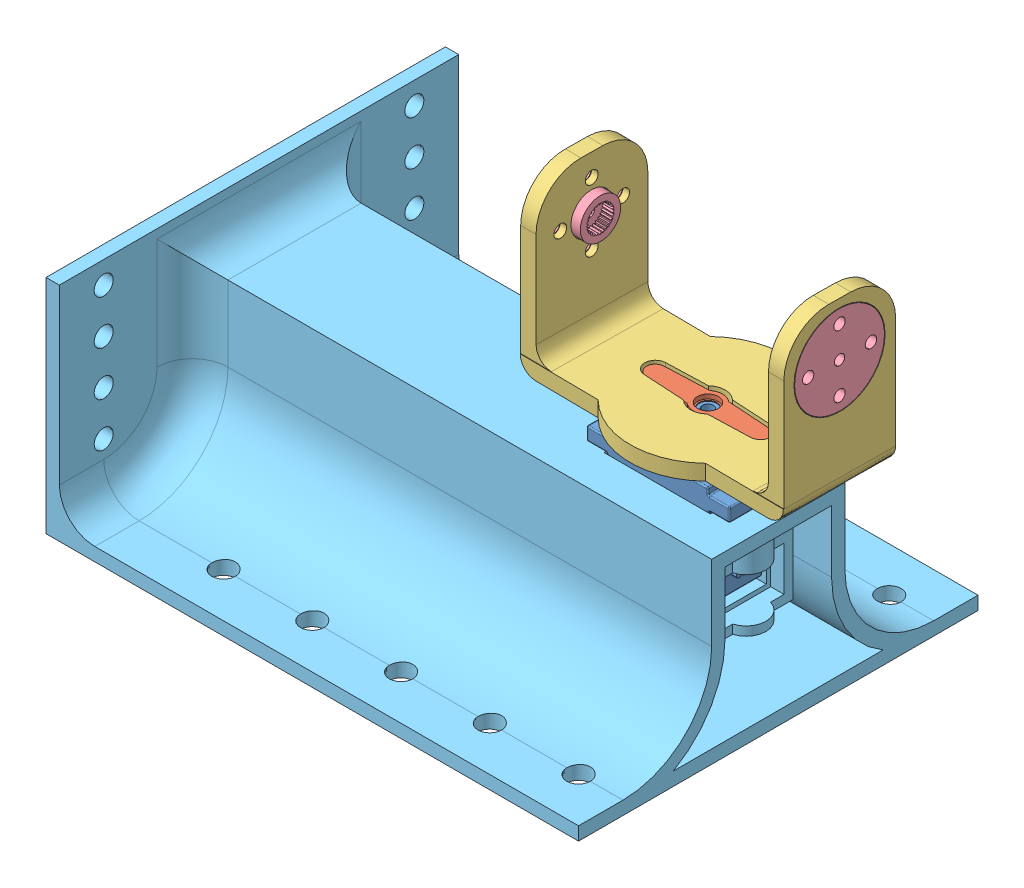
SolidWorks assembly CameraHolder, configuration Predeterminado. Lengths in mm.
Overall size (134.35 90.68 90).
6 component instances, 5 part files, 14 mates.
Components (placement in the parent):
- MG90S-1: MG90S [Default] at (-1.0795 -35.2179 32.5) size (32.2 32.5 12.4)
- Microservo horn-1: Microservo horn [По умолчанию] at (4.1705 -1.5379 32.5) x (0.999933 0 0.011606) z (0 -1 0) size (28 6.6 4.68)
- cameraHolder-1: cameraHolder [Predeterminado] at (4.1705 -4.5379 32.5) x (-0.011606 0 0.999933) z (-0.999933 0 -0.011606) size (35 40.2 60)
- MG955 horn-1: MG955 horn [Default] at (-23.8276 21.9621 32.175) x (0.011606 0 -0.999933) z (0 1 0) size (20 5.5 20)
- MG955 horn-4: MG955 horn [Default] at (32.1686 21.9621 32.825) x (-0.011606 0 0.999933) z (0 1 0) size (20 5.5 20)
- Soporte_motor-1: Soporte_motor [Predeterminado] at (20.0205 -36.7179 32.5) x (0 0 -1) z (1 0 0) size (90 50 120)
Mates (geometry in assembly coordinates):
- Concéntrica1: concentric aligned: cylinder of MG90S-1 through (4.1705 -5.2179 32.5) axis (0 1 0) radius 1.25; cylinder of Microservo horn-1 through (4.1705 -3.5379 32.5) axis (0 1 0) radius 2
- Coincidente1: coincident anti-aligned: plane of MG90S-1 through (4.1705 -6.2179 32.5) normal (0 1 0); plane of Microservo horn-1 through (4.1705 -6.2179 32.5) normal (0 -1 0)
- Concéntrica2: concentric aligned: cylinder of MG90S-1 through (4.1705 -5.2179 32.5) axis (0 1 0) radius 1.25; cylinder of cameraHolder-1 through (4.1705 -4.5379 32.5) axis (0 1 0) radius 3.6
- Distancia1: distance = 1 mm aligned: plane of Microservo horn-1 through (4.1705 -3.5379 32.5) normal (0 -1 0); plane of cameraHolder-1 through (4.1705 -4.5379 32.5) normal (0 -1 0)
- Coincidente3: coincident aligned: plane of Microservo horn-1 through (4.1705 -1.5379 32.5) normal (-0.011606 0 0.999933); plane of cameraHolder-1 through (4.1705 -4.5379 32.5) normal (-0.011606 0 0.999933)
- Coincidente4: coincident aligned: plane of cameraHolder-1 through (-25.8275 -4.5379 32.1518) normal (-0.999933 0 -0.011606); plane of MG955 horn-1 through (-25.8275 21.9621 32.1518) normal (-0.999933 0 -0.011606)
- Tangente1: tangent aligned: cylinder of MG955 horn-1 through (-25.8275 21.9621 32.1518) axis (0.999933 0 0.011606) radius 10; plane of assembly through (0 31.9621 0) normal (0 1 0)
- Coincidente6: coincident anti-aligned: plane of MG955 horn-1 through (-23.8276 21.9621 32.175) normal (0.011606 0 -0.999933); plane of cameraHolder-1 through (4.1705 -4.5379 32.5) normal (-0.011606 0 0.999933)
- Coincidente7: coincident aligned: plane of cameraHolder-1 through (34.1685 -4.5379 32.8482) normal (0.999933 0 0.011606); plane of MG955 horn-4 through (34.1685 21.9621 32.8482) normal (0.999933 0 0.011606)
- Tangente3: tangent aligned: cylinder of MG955 horn-4 through (34.1685 21.9621 32.8482) axis (-0.999933 0 -0.011606) radius 10; plane of assembly through (0 31.9621 0) normal (0 1 0)
- Coincidente8: coincident aligned: plane of cameraHolder-1 through (4.1705 -4.5379 32.5) normal (-0.011606 0 0.999933); plane of MG955 horn-4 through (32.1686 21.9621 32.825) normal (-0.011606 0 0.999933)
- Coincidente9: coincident anti-aligned: plane of Microservo horn-1 through (4.1705 -1.5379 32.5) normal (0 0 1); plane of Soporte_motor-1 through (20.0205 -36.7179 32.5) normal (0 0 -1)
- Coincidente10: coincident anti-aligned: plane of MG90S-1 through (-1.0795 -16.7179 32.5) normal (0 -1 0); plane of Soporte_motor-1 through (-99.9795 -16.7179 32.5) normal (0 1 0)
- Distancia2: distance = 5 mm aligned: plane of Soporte_motor-1 through (20.0205 -36.7179 32.5) normal (1 0 0); plane of MG90S-1 through (15.0205 -13.7179 38.5) normal (1 0 0)
